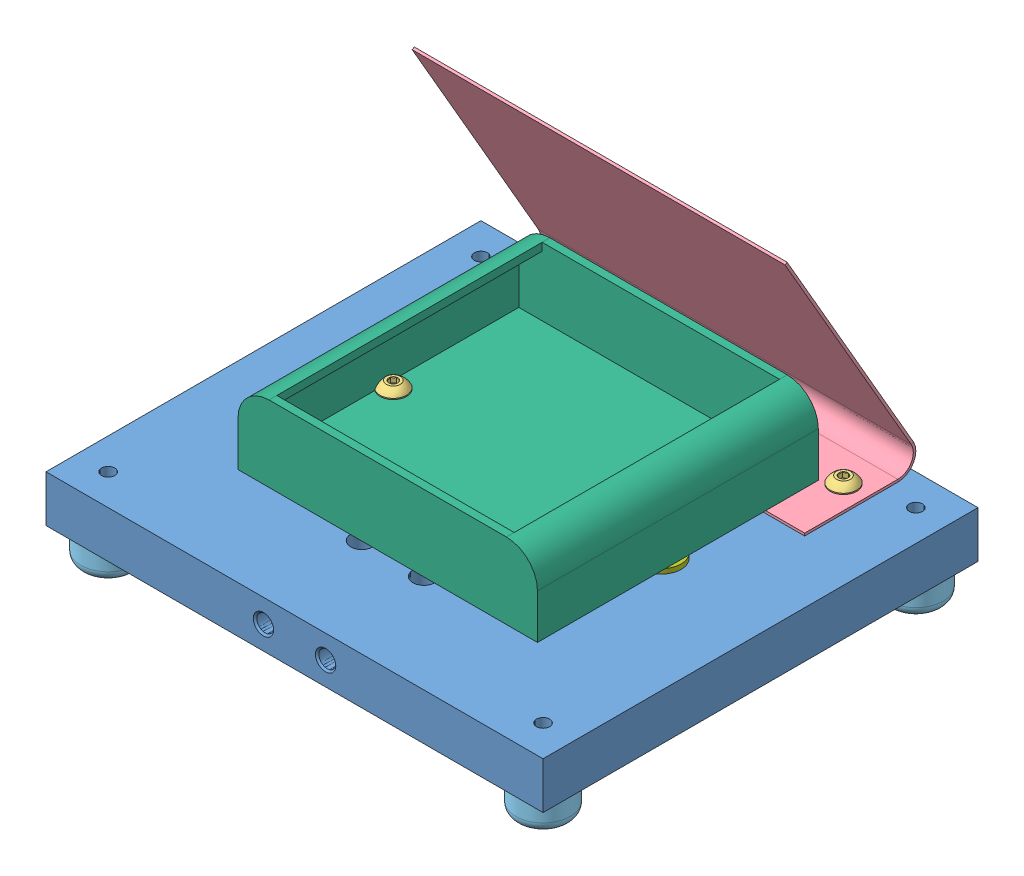
SolidWorks assembly Base_assy, configuration Default. Lengths in mm.
Overall size (103.02 66.13 91.14).
17 component instances, 7 part files, 39 mates.
Components (placement in the parent):
- Base-1: Base [Default] at (101.6 22.2369 0) x (1 0 0) z (0 -1 0) size (101.6 88.9 9.53)
- 4_40_THIN_LOCKNUT_90633A005-1: 4_40_THIN_LOCKNUT_90633A005 [90633A005] at (17.4625 12.7119 10.033) x (0.738933 0 0.673778) z (0.673778 0 -0.738933) size (6.35 2.86 7.33)
- 4_40-625-Stainless-92949A811-14: 4_40-625-Stainless-92949A811 [92949A112] at (17.4625 24.2435 10.033) x (-0.985481 0 0.169785) z (0 1 0) size (5.41 5.41 17.74)
- Plate-1: Plate [Default] at (88.9 22.2369 3.683) x (0 0 -1) z (1 0 0) size (26.76 50.26 76.2)
- 9541K800_BUMPER WITH THREADED STUD_new-1: 9541K800_BUMPER WITH THREADED STUD_new [9541K8] at (6.35 12.7119 6.35) x (-0.997902 0 0.064746) z (0.064746 0 0.997902) size (11.11 12.97 11.11)
- 9541K800_BUMPER WITH THREADED STUD_new-2: 9541K800_BUMPER WITH THREADED STUD_new [9541K8] at (6.35 12.7119 82.55) x (-0.985271 0 -0.170998) z (-0.170998 0 0.985271) size (11.11 12.97 11.11)
- 9541K800_BUMPER WITH THREADED STUD_new-3: 9541K800_BUMPER WITH THREADED STUD_new [9541K8] at (95.25 12.7119 6.35) x (-0.837169 0 -0.546944) z (-0.546944 0 0.837169) size (11.11 12.97 11.11)
- 9541K800_BUMPER WITH THREADED STUD_new-4: 9541K800_BUMPER WITH THREADED STUD_new [9541K8] at (95.25 12.7119 82.55) x (-0.925243 0 -0.379375) z (-0.379375 0 0.925243) size (11.11 12.97 11.11)
- BC4AA_battery_holder-1: BC4AA_battery_holder [Default] at (20.193 23.2021 69.85) x (0 0 -1) z (1 0 0) size (57.4 15.58 61.21)
- 4_40_THIN_LOCKNUT_90633A005-3: 4_40_THIN_LOCKNUT_90633A005 [90633A005] at (84.1375 12.7119 10.033) x (0.85267 0 0.52245) z (0.52245 0 -0.85267) size (6.35 2.86 7.33)
- 4_40-625-Stainless-92949A811-15: 4_40-625-Stainless-92949A811 [92949A112] at (84.1375 24.2435 10.033) x (-0.997586 0 -0.069437) z (0 1 0) size (5.41 5.41 17.74)
- 4_40_THIN_LOCKNUT_90633A005-4: 4_40_THIN_LOCKNUT_90633A005 [90633A005] at (78.232 12.7119 41.275) x (0.945248 0 0.326353) z (0.326353 0 -0.945248) size (6.35 2.86 7.33)
- 4_40-625-Stainless-92949A811-16: 4_40-625-Stainless-92949A811 [92949A112] at (78.232 26.2882 41.275) x (-0.935392 0 -0.353613) z (0 1 0) size (5.41 5.41 17.74)
- 4_40_THIN_LOCKNUT_90633A005-5: 4_40_THIN_LOCKNUT_90633A005 [90633A005] at (23.368 12.7119 41.275) x (0.995414 0 0.095663) z (0.095663 0 -0.995414) size (6.35 2.86 7.33)
- 4_40-625-Stainless-92949A811-17: 4_40-625-Stainless-92949A811 [92949A112] at (23.368 26.2882 41.275) x (0.975064 0 -0.221925) z (0 1 0) size (5.41 5.41 17.74)
- 4_40-Washer_AL_93286A005-new-1: 4_40-Washer_AL_93286A005-new [93286A005] at (23.368 23.2021 41.275) x (0 -1 0) z (0 0 1) size (0.97 7.92 7.92)
- 4_40-Washer_AL_93286A005-new-2: 4_40-Washer_AL_93286A005-new [93286A005] at (78.232 23.2021 41.275) x (0 -1 0) z (0.188455 0 0.982082) size (0.97 7.92 7.92)
Mates (geometry in assembly coordinates):
- Coincident23: coincident anti-aligned: plane of Plate-1 through (88.9 22.7449 3.175) normal (0 1 0); plane of ? through (22.0643 22.7449 18.289) normal (0 -1 0)
- Coincident16: coincident anti-aligned: plane of Base-1 through (101.6 12.7119 0) normal (0 -1 0); plane of 9541K800_BUMPER WITH THREADED STUD_new-1 through (2.0706 12.7119 6.6277) normal (0 1 0)
- Concentric18: concentric aligned: cylinder of Base-1 through (6.35 12.7119 6.35) axis (0 -1 0) radius 1.3526; cylinder of 9541K800_BUMPER WITH THREADED STUD_new-1 through (6.35 6.3619 6.35) axis (0 -1 0) radius 5.5563
- Coincident15: coincident anti-aligned: plane of Base-1 through (101.6 12.7119 0) normal (0 -1 0); plane of 9541K800_BUMPER WITH THREADED STUD_new-2 through (2.1248 12.7119 81.8167) normal (0 1 0)
- Concentric17: concentric aligned: cylinder of Base-1 through (6.35 12.7119 82.55) axis (0 -1 0) radius 1.3526; cylinder of 9541K800_BUMPER WITH THREADED STUD_new-2 through (6.35 6.3619 82.55) axis (0 -1 0) radius 5.5563
- Coincident20: coincident anti-aligned: plane of Base-1 through (101.6 12.7119 0) normal (0 -1 0); plane of ? through (19.05 12.7119 9.9949) normal (0 1 0)
- Concentric21: concentric aligned: cylinder of Base-1 through (19.05 12.7119 12.7) axis (0 -1 0) radius 1.632; cylinder of ? through (19.05 11.2133 12.7) axis (0 -1 0) radius 2.7051
- Coincident42: coincident anti-aligned: plane of Base-1 through (101.6 12.7119 0) normal (0 -1 0); plane of 9541K800_BUMPER WITH THREADED STUD_new-3 through (91.6599 12.7119 4.0045) normal (0 1 0)
- Concentric39: concentric aligned: cylinder of Base-1 through (95.25 12.7119 6.35) axis (0 -1 0) radius 1.3526; cylinder of 9541K800_BUMPER WITH THREADED STUD_new-3 through (95.25 6.3619 6.35) axis (0 -1 0) radius 5.5563
- Coincident43: coincident anti-aligned: plane of Base-1 through (101.6 12.7119 0) normal (0 -1 0); plane of 9541K800_BUMPER WITH THREADED STUD_new-4 through (91.2822 12.7119 80.9231) normal (0 1 0)
- Concentric40: concentric aligned: cylinder of Base-1 through (95.25 12.7119 82.55) axis (0 -1 0) radius 1.3526; cylinder of 9541K800_BUMPER WITH THREADED STUD_new-4 through (95.25 6.3619 82.55) axis (0 -1 0) radius 5.5563
- Parallel1: parallel aligned: plane of Base-1 through (101.6 12.7119 88.9) normal (0 0 1); plane of BC4AA_battery_holder-1 through (20.193 24.7896 69.85) normal (0 0 1)
- Distance1: distance = 19.05 mm aligned: plane of BC4AA_battery_holder-1 through (20.193 24.7896 69.85) normal (0 0 1); plane of Base-1 through (101.6 12.7119 88.9) normal (0 0 1)
- Width1: width anti-aligned: plane of BC4AA_battery_holder-1 through (20.193 24.7896 69.85) normal (-1 0 0); plane of BC4AA_battery_holder-1 through (81.407 24.7896 69.85) normal (1 0 0); plane of Base-1 through (0 12.7119 0) normal (-1 0 0); plane of Base-1 through (101.6 12.7119 0) normal (1 0 0)
- Concentric41: concentric anti-aligned: cylinder of 4_40-625-Stainless-92949A811-14 through (17.4625 24.2435 10.033) axis (0 1 0) radius 2.7051; cylinder of Base-1 through (17.4625 12.7119 10.033) axis (0 -1 0) radius 1.632
- Coincident46: coincident anti-aligned: plane of 4_40_THIN_LOCKNUT_90633A005-1 through (11.4111 12.7119 11.9573) normal (0 1 0); plane of Base-1 through (101.6 12.7119 0) normal (0 -1 0)
- Concentric43: concentric anti-aligned: cylinder of 4_40_THIN_LOCKNUT_90633A005-1 through (17.4625 8.6638 10.033) axis (0 1 0) radius 1.9297; cylinder of Base-1 through (17.4625 12.7119 10.033) axis (0 -1 0) radius 1.632
- Concentric44: concentric anti-aligned: cylinder of Base-1 through (84.1375 12.7119 10.033) axis (0 -1 0) radius 1.632; cylinder of 4_40-625-Stainless-92949A811-15 through (84.1375 24.2435 10.033) axis (0 1 0) radius 2.7051
- Coincident48: coincident anti-aligned: plane of Base-1 through (101.6 12.7119 0) normal (0 -1 0); plane of 4_40_THIN_LOCKNUT_90633A005-3 through (78.5572 12.7119 13.0633) normal (0 1 0)
- Concentric45: concentric anti-aligned: cylinder of Base-1 through (84.1375 12.7119 10.033) axis (0 -1 0) radius 1.632; cylinder of 4_40_THIN_LOCKNUT_90633A005-3 through (84.1375 8.6638 10.033) axis (0 1 0) radius 1.9297
- Coincident50: coincident anti-aligned: plane of Base-1 through (101.6 12.7119 0) normal (0 -1 0); plane of 4_40_THIN_LOCKNUT_90633A005-4 through (73.4361 12.7119 45.437) normal (0 1 0)
- Coincident51: coincident anti-aligned: plane of BC4AA_battery_holder-1 through (20.193 24.7896 69.85) normal (0 1 0); plane of 4_40-625-Stainless-92949A811-16 through (79.1886 24.7896 38.7447) normal (0 -1 0)
- Concentric47: concentric aligned: cylinder of Base-1 through (78.232 22.2369 41.275) axis (0 1 0) radius 1.632; cylinder of 4_40-625-Stainless-92949A811-16 through (78.232 26.2882 41.275) axis (0 1 0) radius 2.7051
- Concentric48: concentric aligned: cylinder of Base-1 through (78.232 22.2369 41.275) axis (0 1 0) radius 1.632; cylinder of 4_40_THIN_LOCKNUT_90633A005-4 through (78.232 8.6638 41.275) axis (0 1 0) radius 1.9297
- Coincident52: coincident anti-aligned: plane of Base-1 through (101.6 12.7119 0) normal (0 -1 0); plane of 4_40_THIN_LOCKNUT_90633A005-5 through (19.6815 12.7119 46.4453) normal (0 1 0)
- Concentric49: concentric aligned: cylinder of Base-1 through (23.368 22.2369 41.275) axis (0 1 0) radius 1.632; cylinder of 4_40-625-Stainless-92949A811-17 through (23.368 26.2882 41.275) axis (0 1 0) radius 2.7051
- Concentric50: concentric aligned: cylinder of Base-1 through (23.368 22.2369 41.275) axis (0 1 0) radius 1.632; cylinder of 4_40_THIN_LOCKNUT_90633A005-5 through (23.368 8.6638 41.275) axis (0 1 0) radius 1.9297
- Coincident53: coincident anti-aligned: plane of BC4AA_battery_holder-1 through (20.193 24.7896 69.85) normal (0 1 0); plane of 4_40-625-Stainless-92949A811-17 through (23.9683 24.7896 43.9126) normal (0 -1 0)
- Coincident54: coincident anti-aligned: plane of Base-1 through (101.6 12.7119 0) normal (0 -1 0); plane of ? through (24.5404 12.7119 26.139) normal (0 1 0)
- Coincident56: coincident anti-aligned: plane of Base-1 through (101.6 22.2369 0) normal (0 1 0); plane of 4_40-Washer_AL_93286A005-new-1 through (23.368 22.2369 41.275) normal (0 -1 0)
- Concentric51: concentric aligned: cylinder of Base-1 through (23.368 22.2369 41.275) axis (0 1 0) radius 1.632; cylinder of 4_40-Washer_AL_93286A005-new-1 through (23.368 22.2369 41.275) axis (0 1 0) radius 1.5875
- Coincident57: coincident anti-aligned: plane of Base-1 through (101.6 22.2369 0) normal (0 1 0); plane of 4_40-Washer_AL_93286A005-new-2 through (78.232 22.2369 41.275) normal (0 -1 0)
- Concentric52: concentric aligned: cylinder of Base-1 through (78.232 22.2369 41.275) axis (0 1 0) radius 1.632; cylinder of 4_40-Washer_AL_93286A005-new-2 through (78.232 22.2369 41.275) axis (0 1 0) radius 1.5875
- Coincident58: coincident anti-aligned: plane of BC4AA_battery_holder-1 through (20.193 23.2021 69.85) normal (0 -1 0); plane of 4_40-Washer_AL_93286A005-new-2 through (78.232 23.2021 41.275) normal (0 1 0)
- Coincident59: coincident anti-aligned: plane of Plate-1 through (88.9 22.7449 3.683) normal (0 1 0); plane of 4_40-625-Stainless-92949A811-15 through (84.3253 22.7449 7.3344) normal (0 -1 0)
- Coincident60: coincident anti-aligned: plane of Base-1 through (101.6 22.2369 0) normal (0 1 0); plane of Plate-1 through (88.9 22.2369 3.683) normal (0 -1 0)
- Coincident61: coincident anti-aligned: plane of 4_40-625-Stainless-92949A811-14 through (17.0032 22.7449 7.3672) normal (0 -1 0); plane of Plate-1 through (88.9 22.7449 3.683) normal (0 1 0)
- Width2: width anti-aligned: plane of Plate-1 through (88.9 22.7449 3.683) normal (1 0 0); plane of Plate-1 through (12.7 22.7449 3.683) normal (-1 0 0); plane of Base-1 through (0 12.7119 0) normal (-1 0 0); plane of Base-1 through (101.6 12.7119 0) normal (1 0 0)
- Tangent2: tangent aligned: plane of Base-1 through (101.6 12.7119 0) normal (0 0 -1); cylinder of Plate-1 through (12.7 25.9199 3.683) axis (-1 0 0) radius 3.683
